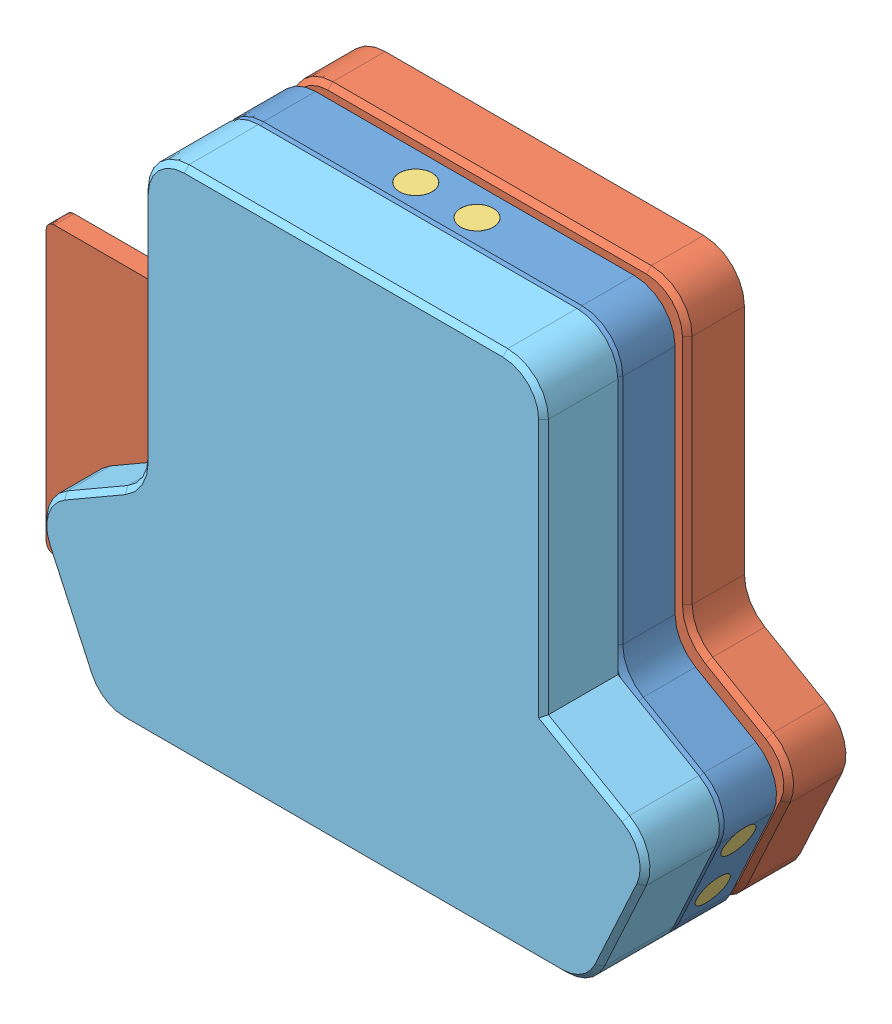
SolidWorks assembly Mechanical_tool_changer, configuration Default. Lengths in mm.
Overall size (80.88 62.5 24.59).
13 component instances, 5 part files, 31 mates.
Components (placement in the parent):
- carriage_part-1: carriage_part [Default] at (40.7969 -57.6875 8.7639) size (76.75 62.5 7)
- tool_part-1: tool_part [Default] at (40.7969 -57.6875 7.2705) x (-1 0 0) z (0 0 -1) size (79.43 62.5 23.49)
- kinematic_dowel-1: kinematic_dowel [Default] at (-24.9628 -45.1998 12.2639) x (0.418794 -0.908081 0) z (0 0 1) size (4 25 4)
- kinematic_dowel-2: kinematic_dowel [Default] at (-21.8219 -52.0104 12.2639) x (0.408369 -0.885476 -0.221738) z (0.092862 -0.201356 0.975106) size (4 25 4)
- kinematic_dowel-4: kinematic_dowel [Default] at (46.556 -45.2017 12.2639) x (0.315525 0.684064 -0.657648) z (0.275451 0.597183 0.753325) size (4 25 4)
- kinematic_dowel-6: kinematic_dowel [Default] at (43.4147 -52.0121 12.2639) x (0.218002 0.472633 -0.853869) z (0.357637 0.775364 0.520487) size (4 25 4)
- kinematic_dowel-8: kinematic_dowel [Default] at (14.5479 4.8124 12.2639) x (-0.925785 0.000024 0.37805) z (0.37805 -0.00001 0.925785) size (4 25 4)
- kinematic_dowel-10: kinematic_dowel [Default] at (7.0479 4.8126 12.2639) x (-0.707454 0.000019 0.70676) z (0.70676 -0.000019 0.707454) size (4 25 4)
- kinematic_ball-1: kinematic_ball [Default] at (10.7976 -6.1875 6.3531) x (0.837619 -0.546255 0) z (-0.546255 -0.837619 0) size (10 9.58 10)
- kinematic_ball-6: kinematic_ball [Default] at (-13.4035 -43.9984 6.3531) x (1 0 0) z (0 -1 0) size (10 9.58 10)
- kinematic_ball-8: kinematic_ball [Default] at (34.9967 -43.9996 6.3531) x (1 0 0) z (0 -1 0) size (10 9.58 10)
- kinematic_dowel-12: kinematic_dowel [Default] at (10.7969 -45.3375 19.7639) x (0.377911 0 -0.925842) z (0.925842 0 0.377911) size (4 25 4)
- tool_changer_backplate-1: tool_changer_backplate [Default] at (40.7969 -57.6875 15.7639) size (73.85 62.5 9.1)
Mates (geometry in assembly coordinates):
- Width1: width anti-aligned: plane of tool_part-1 through (35.2969 -57.6875 0.2705) normal (1 0 0); plane of carriage_part-1 through (-13.7031 -57.6875 0.2705) normal (-1 0 0); plane of tool_part-1 through (-13.7031 -31.5145 15.7639) normal (-1 0 0); plane of carriage_part-1 through (35.2969 4.8125 15.7639) normal (1 0 0)
- Width2: width anti-aligned: plane of tool_part-1 through (40.7969 4.8125 0.2705) normal (0 1 0); plane of carriage_part-1 through (40.7969 -57.6875 0.2705) normal (0 -1 0); plane of tool_part-1 through (40.7969 -57.6875 15.7639) normal (0 -1 0); plane of carriage_part-1 through (-13.7031 4.8125 15.7639) normal (0 1 0)
- Concentric1: concentric aligned: cylinder of carriage_part-1 through (-25.8709 -45.6186 12.2639) axis (0.908081 0.418794 0) radius 2; circle of kinematic_dowel-1
- Coincident4: coincident anti-aligned: plane of carriage_part-1 through (-2.2608 -34.7299 12.2639) normal (-0.908081 -0.418794 0); plane of kinematic_dowel-1 through (-2.2608 -34.7299 12.2639) normal (0.908081 0.418794 0)
- Concentric2: concentric aligned: cylinder of carriage_part-1 through (-22.73 -52.4292 12.2639) axis (0.908081 0.418794 0) radius 2; circle of kinematic_dowel-2
- Coincident5: coincident anti-aligned: plane of carriage_part-1 through (0.8801 -41.5405 12.2639) normal (-0.908081 -0.418794 0); plane of kinematic_dowel-2 through (0.8801 -41.5405 12.2639) normal (0.908081 0.418794 0)
- Concentric3: concentric aligned: cylinder of carriage_part-1 through (47.464 -45.6205 12.2639) axis (-0.908059 0.418842 0) radius 2; circle of kinematic_dowel-4
- Coincident6: coincident anti-aligned: plane of carriage_part-1 through (23.8545 -34.7306 12.2639) normal (0.908059 -0.418842 0); plane of kinematic_dowel-4 through (23.8545 -34.7306 12.2639) normal (-0.908059 0.418842 0)
- Concentric4: concentric aligned: cylinder of carriage_part-1 through (44.3227 -52.431 12.2639) axis (-0.908059 0.418842 0) radius 2; circle of kinematic_dowel-6
- Coincident7: coincident anti-aligned: plane of carriage_part-1 through (20.7132 -41.5411 12.2639) normal (0.908059 -0.418842 0); plane of kinematic_dowel-6 through (20.7132 -41.5411 12.2639) normal (-0.908059 0.418842 0)
- Concentric5: concentric aligned: cylinder of carriage_part-1 through (14.5479 5.8124 12.2639) axis (-0.000026 -1 0) radius 2; circle of kinematic_dowel-8
- Coincident8: coincident anti-aligned: plane of carriage_part-1 through (14.5472 -20.1876 12.2639) normal (0.000026 1 0); plane of kinematic_dowel-8 through (14.5472 -20.1876 12.2639) normal (-0.000026 -1 0)
- Concentric6: concentric aligned: cylinder of carriage_part-1 through (7.0479 5.8126 12.2639) axis (-0.000026 -1 0) radius 2; circle of kinematic_dowel-10
- Coincident9: coincident anti-aligned: plane of carriage_part-1 through (7.0472 -20.1874 12.2639) normal (0.000026 1 0); plane of kinematic_dowel-10 through (7.0472 -20.1874 12.2639) normal (-0.000026 -1 0)
- Coincident10: coincident anti-aligned: plane of Part1-1 through (40.7969 -57.6875 1.7705) normal (0 0 1); circle of kinematic_ball-1
- Concentric7: concentric aligned: circle of Part1-1; circle of kinematic_ball-1
- Coincident11: coincident aligned: plane of tool_part-1 through (40.7969 -57.6875 1.7705) normal (0 0 1); circle of kinematic_ball-2
- Concentric8: concentric aligned: circle of Part1-1; circle of kinematic_ball-2
- Coincident12: coincident aligned: plane of tool_part-1 through (40.7969 -57.6875 1.7705) normal (0 0 1); circle of kinematic_ball-4
- Concentric9: concentric aligned: circle of Part1-1; circle of kinematic_ball-4
- Concentric10: concentric aligned: circle of Part1-1; circle of kinematic_ball-6
- Coincident14: coincident anti-aligned: plane of Part1-1 through (40.7969 -57.6875 1.7705) normal (0 0 1); plane of kinematic_ball-6 through (-13.4035 -43.9984 1.7705) normal (0 0 -1)
- Concentric12: concentric anti-aligned: circle of Part1-1; circle of kinematic_ball-8
- Coincident15: coincident anti-aligned: plane of Part1-1 through (40.7969 -57.6875 1.7705) normal (0 0 1); plane of kinematic_ball-8 through (34.9967 -43.9996 1.7705) normal (0 0 -1)
- Tangent3: tangent anti-aligned: cylinder of kinematic_dowel-10 through (7.0472 -20.1874 12.2639) axis (0.000026 1 0) radius 2; sphere of kinematic_ball-1
- Concentric13: concentric aligned: cylinder of tool_part-1 through (10.7969 -45.7772 19.7639) axis (0 1 0) radius 2.1; circle of kinematic_dowel-12
- Width3: width anti-aligned: plane of tool_part-1 through (6.2969 -25.8375 48.4072) normal (0 1 0); plane of kinematic_dowel-12 through (6.2969 -39.8375 48.4072) normal (0 -1 0); plane of tool_part-1 through (10.7969 -45.3375 19.7639) normal (0 -1 0); plane of kinematic_dowel-12 through (10.7969 -20.3375 19.7639) normal (0 1 0)
- InPlace2: in place: plane of carriage_part-1 through (40.7969 -57.6875 15.7639) normal (0 0 1); plane of ? through (0 0 15.7639) normal (0 0 1); moOrthogonalPlaneRef_w of carriage_part-1 through (40.7969 -57.6875 15.7639) normal (0 0 1); plane of ? through (0 0 15.7639) normal (0 1 0); plane of carriage_part-1 through (40.7969 -57.6875 15.7639) normal (0 0 1); plane of ? through (0 0 15.7639) normal (1 0 0); plane of carriage_part-1 through (40.7969 -57.6875 15.7639) normal (0 0 1); unknown of tool_changer_backplate-1
- Coincident16: coincident aligned: plane of ?; plane of ?
- Coincident17: coincident aligned: moOrthogonalPlaneRef_w of carriage_part-1 through (40.7969 -57.6875 15.7639) normal (0 1 0); plane of Part2^Mechanical_tool_changer-1 through (40.7969 -57.6875 15.7639) normal (0 1 0)
- Coincident18: coincident anti-aligned: moOrthogonalPlaneRef_w of carriage_part-1 through (40.7969 -57.6875 15.7639) normal (-1 0 0); plane of Part2^Mechanical_tool_changer-1 through (40.7969 -57.6875 15.7639) normal (1 0 0)
